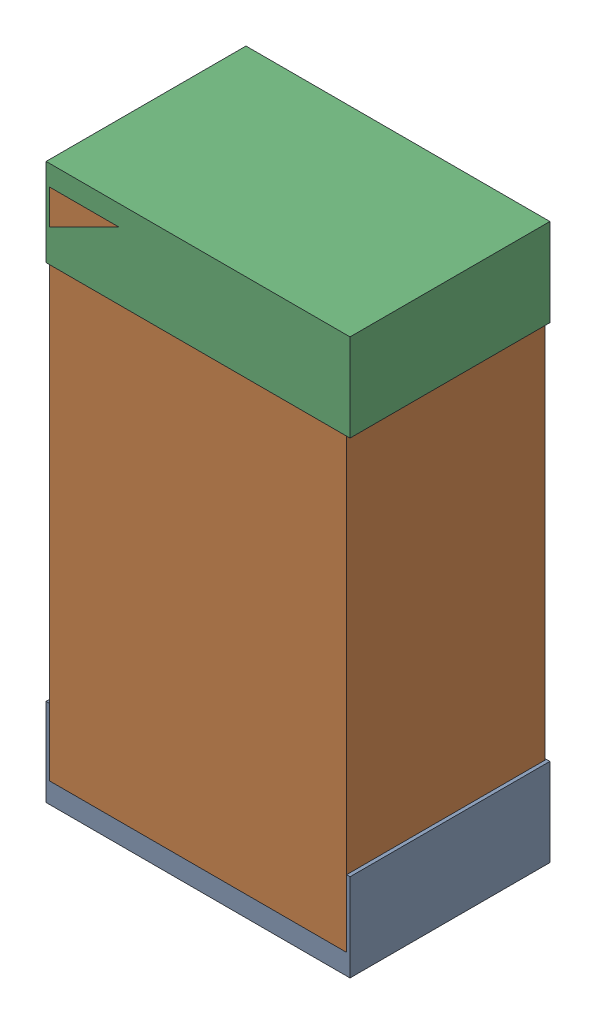
SolidWorks assembly R42Kanaloa_v2.0.0_Motor, configuration Default. Lengths in mm.
Overall size (1.3 2.38 0.85).
6 component instances, 2 part files, 0 mates.
Components (placement in the parent):
- 330415056-1: 330415056 [Default] at (127 124.027 -1.9574) size (1.3 0.38 0.85)
  - Extruded_2-1: Extruded_2 [Default] at origin size (1.3 0.38 0.85)
- 334787376-1: 334787376 [Default] at (127 125.027 -1.9524) size (1.27 2.2 0.85)
  - Extruded_16-1: Extruded_16 [Default] at origin size (1.27 2.2 0.85)
- 330415056-2: 330415056 [Default] at (127 126.027 -1.9574) size (1.3 0.38 0.85)
  - Extruded_2-1: Extruded_2 [Default] at origin size (1.3 0.38 0.85)
